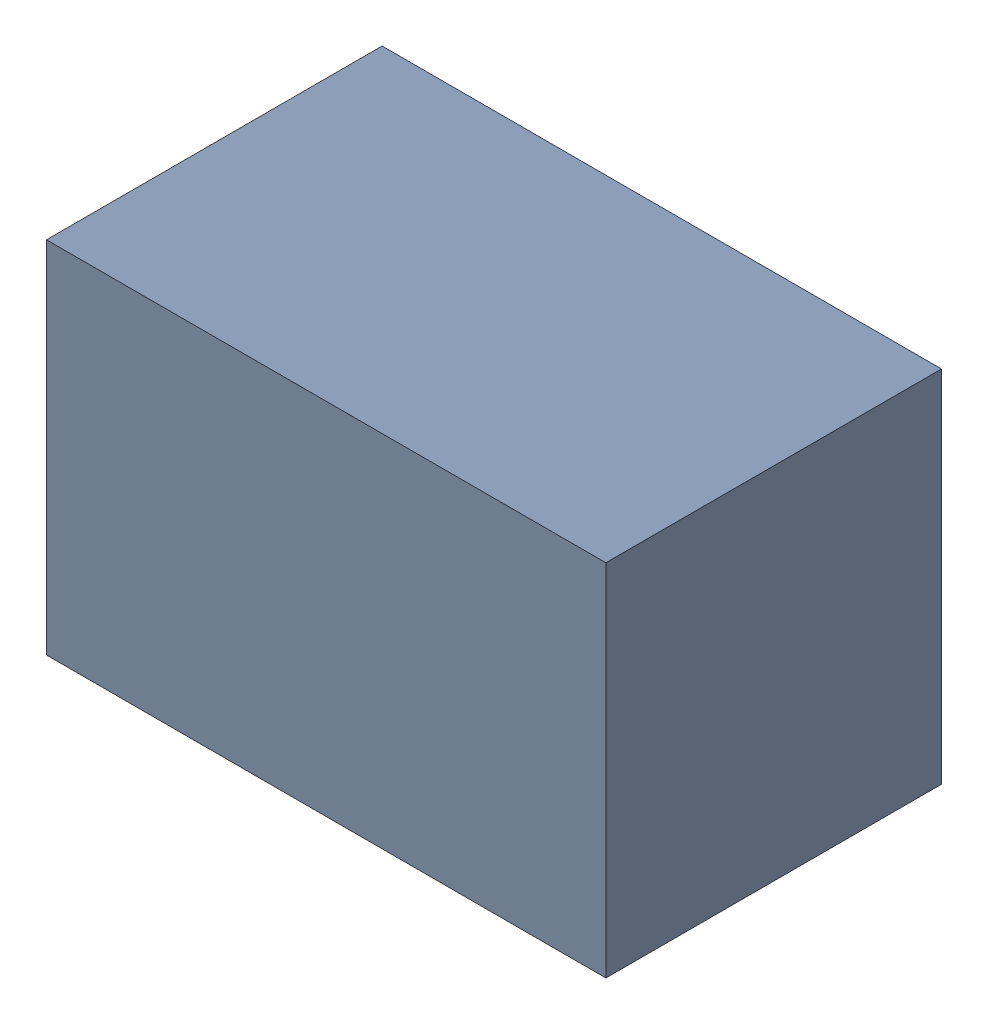
SolidWorks assembly C4_1, configuration Default. Lengths in mm.
Overall size (2.1 1.35 1.26).
2 component instances, 1 part files, 0 mates.
Components (placement in the parent):
- 407985824_1-1: 407985824_1 [Default] at (29.718 12.827 0.0127) size (2.1 1.35 1.26)
  - Extruded_7-1: Extruded_7 [Default] at origin size (2.1 1.35 1.26)
